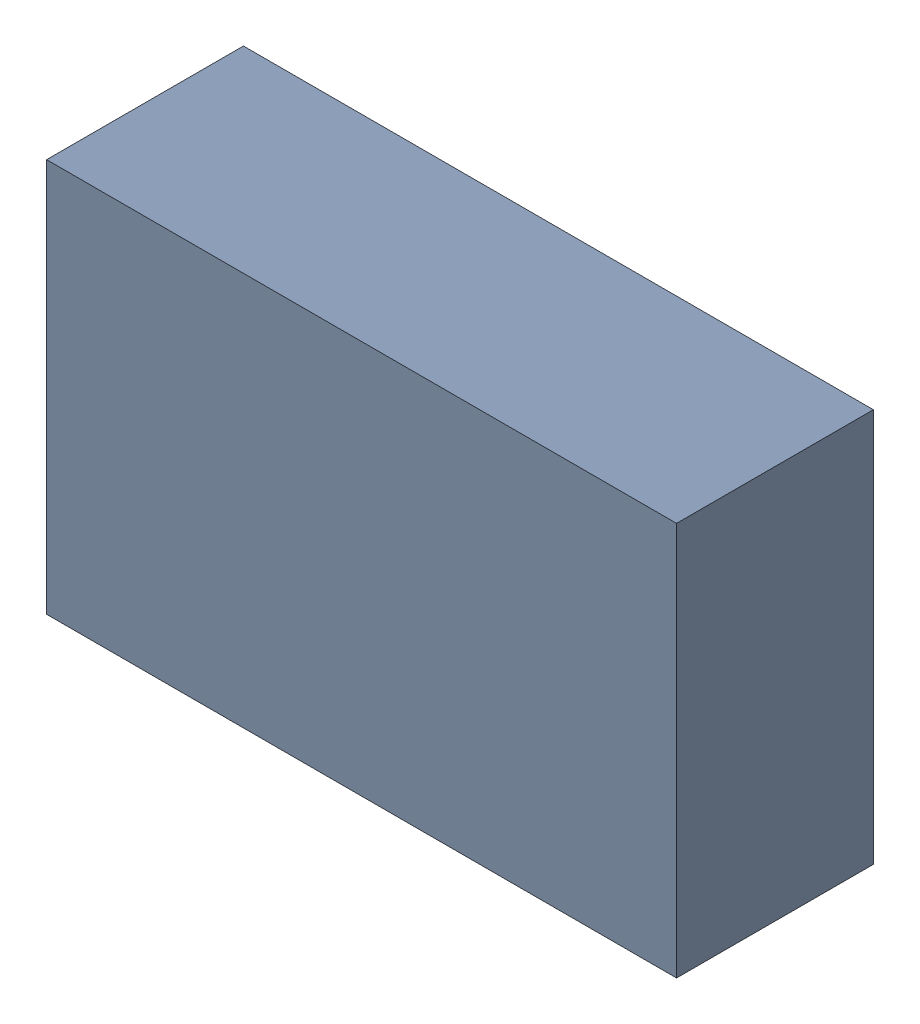
SolidWorks assembly R18, configuration Default. Lengths in mm.
Overall size (2.03 1.27 0.64).
2 component instances, 1 part files, 0 mates.
Components (placement in the parent):
- 948815480-1: 948815480 [Default] at (23.6293 16.4338 0) size (2.03 1.27 0.64)
  - Extruded_15-1: Extruded_15 [Default] at origin size (2.03 1.27 0.64)
